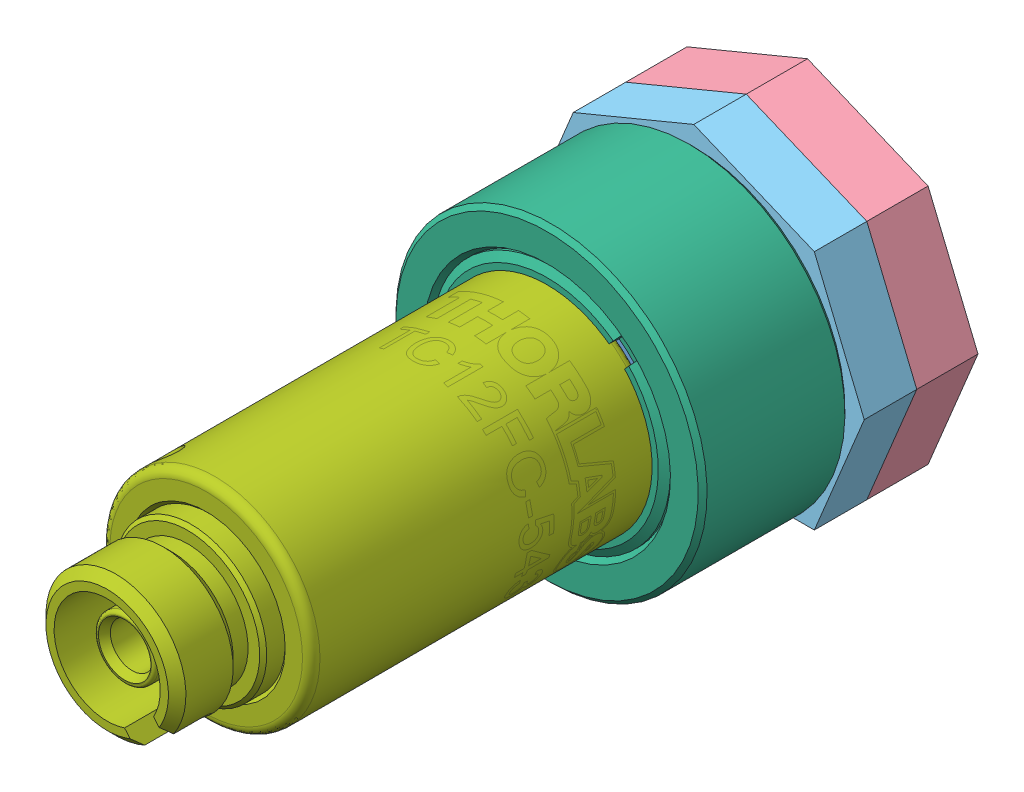
SolidWorks assembly AIM-Lightsheet, configuration Default. Lengths in mm.
Overall size (25.11 25.11 40.02).
7 component instances, 7 part files, 18 mates.
Components (placement in the parent):
- AC127-050-A-Solidworks-1: AC127-050-A-Solidworks [Default] at (-18 -15 -5.5) x (0.997706 0.06769 0) z (0 0 1) size (12.7 12.7 5)
- Edmund Optics - 354280-1: Edmund Optics - 354280 [Default] at (-18 -15 7.28) x (0 0 -1) z (-0.95723 -0.289329 0) size (2.18 6.5 6.5)
- LJ1402L1-A-Solidworks-1: LJ1402L1-A-Solidworks [Default] at (-18 -15 -14.305) size (12 10 2.61)
- PartUno-1: PartUno [Default] at (-18 -15 -17.11) size (19.48 16.63 3.5)
- PartDos-1: PartDos [Default] at (-18 -15 -13.61) size (19.48 16.63 3)
- SM05L03-Solidworks(1)-1: SM05L03-Solidworks(1) [Default] at (-18 -15 -2.228) x (0 0 1) z (-0.667758 -0.744378 0) size (10.41 17.78 17.78)
- TC12FC-543-Solidworks-1: TC12FC-543-Solidworks [Default] at (-18 -15 15.2509) x (0 0 -1) z (0.642054 -0.766659 0) size (25.76 12 12)
Mates (geometry in assembly coordinates):
- Width1: width: plane of LJ1402L1-A-Solidworks-1 through (-12 -15 -33.67) normal (1 0 0); plane of LJ1402L1-A-Solidworks-1 through (-24 -15 -33.67) normal (-1 0 0); cylinder of Edmund Optics - 354280-1 through (-18 -15 7.28) axis (0 0 1) radius 3.25
- Width2: width: plane of LJ1402L1-A-Solidworks-1 through (-12 -20 -15.61) normal (0 -1 0); plane of LJ1402L1-A-Solidworks-1 through (-12 -10 -13.6139) normal (0 1 0); cylinder of Edmund Optics - 354280-1 through (-18 -15 7.28) axis (0 0 1) radius 3.25
- Width3: width: plane of LJ1402L1-A-Solidworks-1 through (-12 -10 -13.6139) normal (0 1 0); plane of LJ1402L1-A-Solidworks-1 through (-12 -20 -15.61) normal (0 -1 0); cylinder of AC127-050-A-Solidworks-1 through (-18 -15 -6.5) axis (0 0 1) radius 6.35
- Width4: width: plane of LJ1402L1-A-Solidworks-1 through (-24 -15 -33.67) normal (-1 0 0); plane of LJ1402L1-A-Solidworks-1 through (-12 -15 -33.67) normal (1 0 0); cylinder of AC127-050-A-Solidworks-1 through (-18 -15 -6.5) axis (0 0 1) radius 6.35
- Distance1: distance = 5.5 mm: plane of Edmund Optics - 354280-1 through (-17.0597 -18.111 5.5) normal (0 0 -1); plane of assembly through (0 0 0) normal (0 0 1)
- Symmetric1: symmetric: plane of LJ1402L1-A-Solidworks-1 through (-24 -15 -33.67) normal (-1 0 0); plane of assembly; plane of LJ1402L1-A-Solidworks-1 through (-12 -15 -33.67) normal (1 0 0)
- Symmetric2: symmetric: plane of LJ1402L1-A-Solidworks-1 through (-12 -20 -15.61) normal (0 -1 0); plane of assembly; plane of LJ1402L1-A-Solidworks-1 through (-12 -10 -13.6139) normal (0 1 0)
- Distance2: distance = 15.61 mm: plane of LJ1402L1-A-Solidworks-1 through (-12 -10 -15.61) normal (0 0 -1); plane of assembly through (0 0 0) normal (0 0 1)
- Distance3: distance = 3 mm: point of AC127-050-A-Solidworks-1; plane of assembly
- Width5: width: plane of PartUno-1 through (-11.85 -20.15 -13.61) normal (-1 0 0); plane of PartUno-1 through (-24.15 -20.15 -13.61) normal (1 0 0); plane of LJ1402L1-A-Solidworks-1 through (-12 -15 -33.67) normal (1 0 0); plane of LJ1402L1-A-Solidworks-1 through (-24 -15 -33.67) normal (-1 0 0)
- Width6: width: plane of PartUno-1 through (-24.15 -20.15 -13.61) normal (0 1 0); plane of PartUno-1 through (-24.15 -9.85 -13.61) normal (0 -1 0); plane of LJ1402L1-A-Solidworks-1 through (-12 -20 -15.61) normal (0 -1 0); plane of LJ1402L1-A-Solidworks-1 through (-12 -10 -13.6139) normal (0 1 0)
- Coincident2: coincident: plane of LJ1402L1-A-Solidworks-1 through (-12 -10 -15.61) normal (0 0 -1); plane of PartUno-1 through (-18 -15 -15.61) normal (0 0 1)
- Coincident3: coincident: plane of PartUno-1 through (-11.1117 -21.8883 -15.61) normal (0.92388 -0.382683 0); plane of PartDos-1 through (-11.1117 -21.8883 -10.61) normal (0.92388 -0.382683 0)
- Coincident5: coincident: plane of PartUno-1 through (-18 -5.2585 -15.61) normal (-0.382683 0.92388 0); plane of PartDos-1 through (-18 -5.2585 -10.61) normal (-0.382683 0.92388 0)
- Coincident6: coincident: plane of PartUno-1 through (-18 -15 -13.61) normal (0 0 1); plane of PartDos-1 through (-18 -15 -13.61) normal (0 0 -1)
- Concentric1: concentric: cylinder of PartDos-1 through (-18 -15 -10.61) axis (0 0 1) radius 6.35; cylinder of SM05L03-Solidworks(1)-1 through (-18 -15 -2.228) axis (0 0 1) radius 6.7945
- Coincident7: coincident: plane of PartDos-1 through (-18 -15 -10.61) normal (0 0 1); plane of SM05L03-Solidworks(1)-1 through (-24.6175 -9.0636 -10.61) normal (0 0 -1)
- Concentric2: concentric: cylinder of SM05L03-Solidworks(1)-1 through (-18 -15 -2.228) axis (0 0 1) radius 8.89; cylinder of TC12FC-543-Solidworks-1 through (-18 -15 15.2509) axis (0 0 1) radius 6
